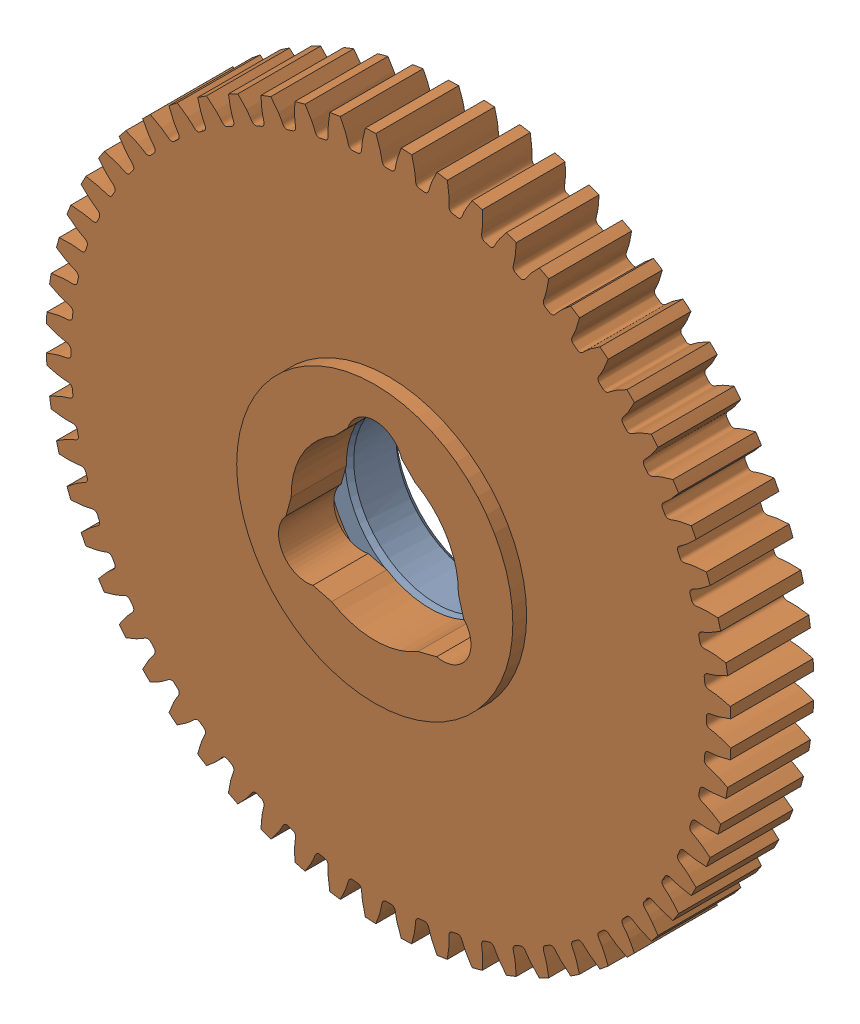
SolidWorks assembly 217-2713-101 Rev1, configuration Default. Lengths in mm.
Overall size (78.91 78.91 12.7).
2 component instances, 2 part files, 0 mates.
Components (placement in the parent):
- 217-2428-022 Rev1-1: 217-2428-022 Rev1 [Default] at (0 0 -3.302) size (28.57 28.57 6.1)
- 217-2713-001_60t Steel-1: 217-2713-001_60t Steel [Default] at origin size (78.91 78.91 11.11)
